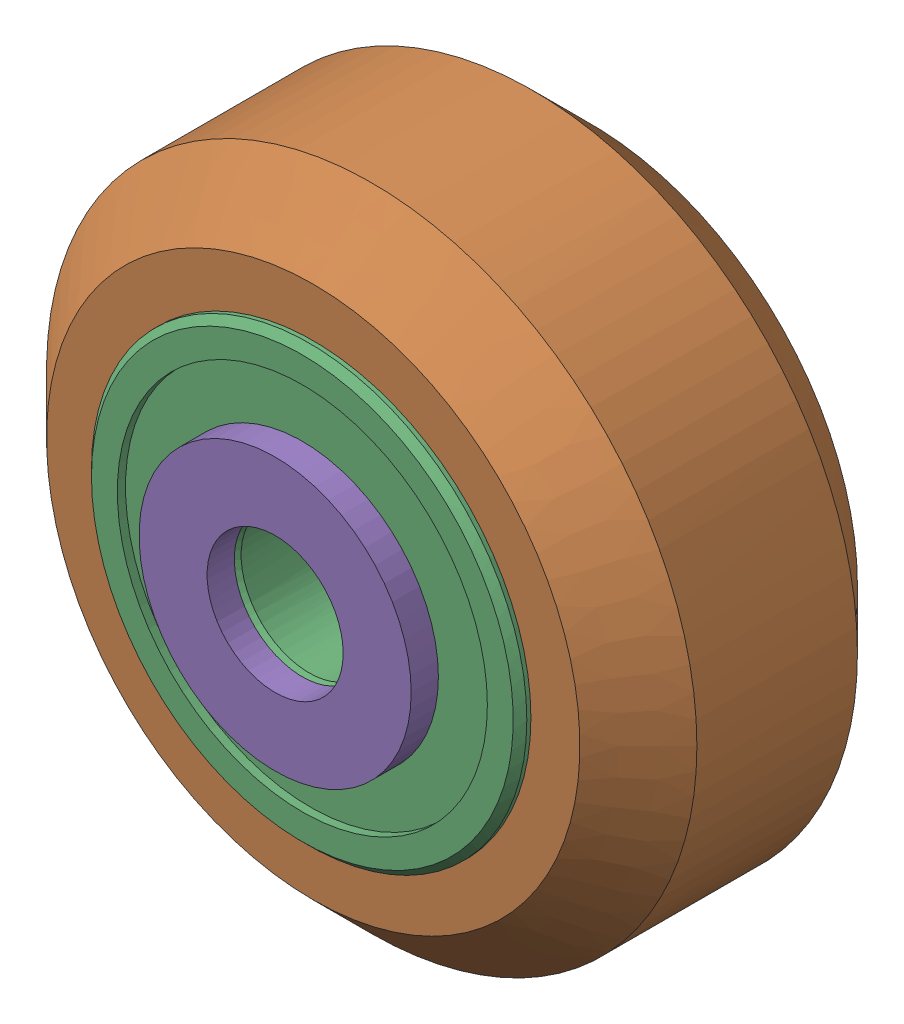
SolidWorks assembly Xtreme Solid V Wheel Kit Assembly_5, configuration Default. Lengths in mm.
Overall size (23.9 23.9 13).
6 component instances, 3 part files, 0 mates.
Components (placement in the parent):
- Precision Shim - 10x5x1mm-1: Precision Shim - 10x5x1mm [Default] at origin size (10 10 1)
- Xtreme Solid V Wheel Assembly_5-1: Xtreme Solid V Wheel Assembly_5 [Default] at (84.85 55.79 -23.5) size (23.9 23.9 11)
  - Xtreme Solid V Wheel-1: Xtreme Solid V Wheel [Default] at (-84.85 -55.79 30) x (0 0 1) z (-1 0 0) size (10.2 23.9 23.9)
  - Wheel+Kit+-+5x16x5mm+Sealed+Radial+Ball+Bearing.step.f3d-1: Wheel+Kit+-+5x16x5mm+Sealed+Radial+Ball+Bearing.step.f3d [Default] at (-84.85 -55.79 30) x (0 1 0) z (-1 0 0) size (16 5 16)
  - Wheel+Kit+-+5x16x5mm+Sealed+Radial+Ball+Bearing.step.f3d-2: Wheel+Kit+-+5x16x5mm+Sealed+Radial+Ball+Bearing.step.f3d [Default] at (-84.85 -55.79 30) x (0 1 0) z (1 0 0) size (16 5 16)
- Precision Shim - 10x5x1mm-2: Precision Shim - 10x5x1mm [Default] at (0 0 12) size (10 10 1)
